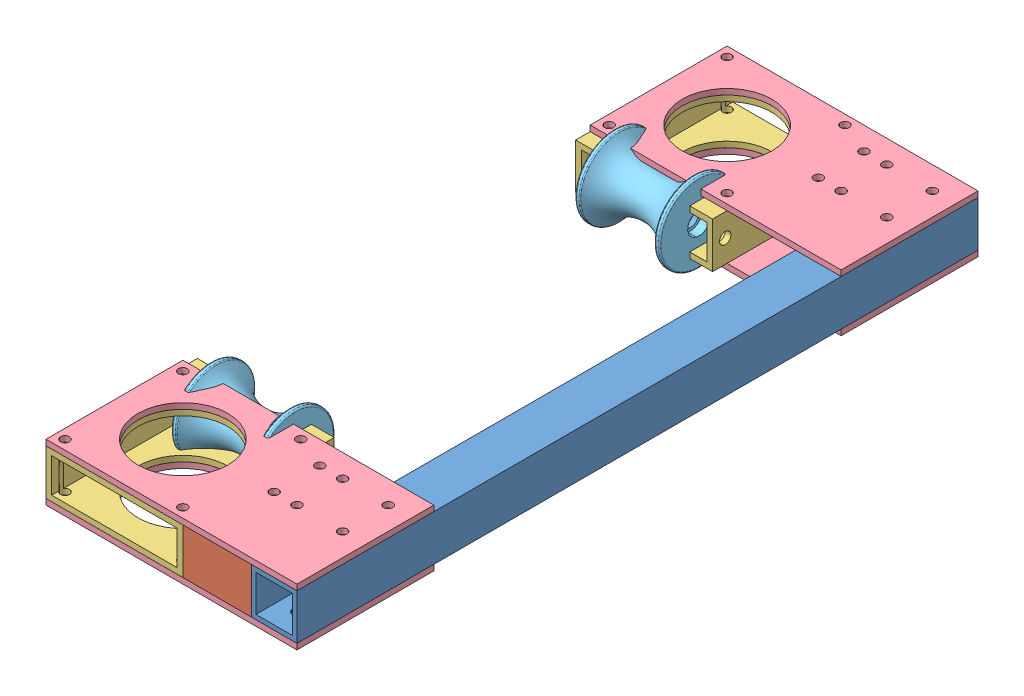
SolidWorks assembly 221-000 Asm, configuration Default. Lengths in mm.
Overall size (139.7 61.76 379.16).
11 component instances, 5 part files, 34 mates.
Components (placement in the parent):
- 221-003-1: 221-003 [Default] at origin size (25.4 25.4 379.16)
- 221-002-1: 221-002 [Default] at (-19.05 25.4 189.5818) x (0 0 -1) z (-1 0 0) size (50.8 25.4 38.1)
- 221-001-1: 221-001 [Default] at (-114.3 25.4 140.3058) x (1 0 0) z (0 1 0) size (76.2 84.26 25.4)
- 221-001-2: 221-001 [Default] at (-114.3 0 -140.3058) x (1 0 0) z (0 -1 0) size (76.2 84.26 25.4)
- 221-002-2: 221-002 [Default] at (-19.05 0 -189.5818) x (0 0 1) z (-1 0 0) size (50.8 25.4 38.1)
- 221-004-1: 221-004 [Rev 1.1] at (0 25.4 0) x (1 0 0) z (0 1 0) size (139.7 76.2 3.17)
- 221-004-2: 221-004 [Rev 1.1] at (0 25.4 302.9636) x (1 0 0) z (0 1 0) size (139.7 76.2 3.17)
- 221-004-3: 221-004 [Rev 1.1] at (0 -3.175 0) x (1 0 0) z (0 1 0) size (139.7 76.2 3.17)
- 221-004-4: 221-004 [Rev 1.1] at (0 -3.175 302.9636) x (1 0 0) z (0 1 0) size (139.7 76.2 3.17)
- 200-001 Roller 3-1: 200-001 Roller 3 [Default] at (-76.2 12.7 -112.3658) x (0 -1 0) z (0 0 1) size (43.94 46.98 43.94)
- 200-001 Roller 3-2: 200-001 Roller 3 [Default] at (-76.2 12.7 112.3658) x (0 -0.780395 0.625287) z (0 0.625287 0.780395) size (43.94 46.98 43.94)
Mates (geometry in assembly coordinates):
- Coincident1: coincident: plane of 221-002-1 through (-38.1 25.4 189.5818) normal (-1 0 0); plane of 221-001-1 through (-38.1 25.4 91.0298) normal (1 0 0)
- Coincident2: coincident: plane of 221-002-1 through (-38.1 25.4 189.5818) normal (0 1 0); plane of 221-001-1 through (-114.3 25.4 91.0298) normal (0 1 0)
- Coincident3: coincident: plane of 221-002-1 through (-38.1 25.4 189.5818) normal (0 0 1); plane of 221-001-1 through (-114.3 25.4 189.5818) normal (0 0 1)
- Coincident4: coincident: plane of 221-003-1 through (0 0 189.5818) normal (-1 0 0); plane of 221-002-1 through (0 25.4 189.5818) normal (1 0 0)
- Coincident5: coincident: plane of 221-003-1 through (0 25.4 189.5818) normal (0 1 0); plane of 221-002-1 through (-38.1 25.4 189.5818) normal (0 1 0)
- Coincident6: coincident: plane of 221-003-1 through (0 0 189.5818) normal (0 0 1); plane of 221-002-1 through (-38.1 25.4 189.5818) normal (0 0 1)
- Coincident7: coincident: plane of 221-001-2 through (-38.1 0 -91.0298) normal (1 0 0); plane of 221-002-2 through (-38.1 0 -189.5818) normal (-1 0 0)
- Coincident8: coincident: plane of 221-001-2 through (-114.3 0 -91.0298) normal (0 -1 0); plane of 221-002-2 through (-38.1 0 -189.5818) normal (0 -1 0)
- Coincident9: coincident: plane of 221-001-2 through (-114.3 0 -189.5818) normal (0 0 -1); plane of 221-002-2 through (-38.1 0 -189.5818) normal (0 0 -1)
- Coincident10: coordinate: point of 221-003-1; point of assembly
- Coincident11: coincident: plane of 221-003-1 through (0 25.4 189.5818) normal (0 1 0); plane of 221-002-2 through (-38.1 25.4 -189.5818) normal (0 1 0)
- Coincident12: coincident: plane of 221-003-1 through (0 0 189.5818) normal (-1 0 0); plane of 221-002-2 through (0 0 -189.5818) normal (1 0 0)
- Coincident13: coincident: plane of 221-003-1 through (0 0 -189.5818) normal (0 0 -1); plane of 221-002-2 through (-38.1 0 -189.5818) normal (0 0 -1)
- Concentric1: concentric: cylinder of 221-001-2 through (-38.1 12.7 -100.584) axis (-1 0 0) radius 3.175; cylinder of ? through (-81.153 12.7 -100.584) axis (-1 0 0) radius 3.81
- Width1: width: plane of ? through (-93.853 12.7 -100.584) normal (-1 0 0); plane of ? through (-58.547 12.7 -100.584) normal (1 0 0); plane of 221-001-2 through (-111.125 0 -66.548) normal (1 0 0); plane of 221-001-2 through (-41.275 0 -66.548) normal (-1 0 0)
- Concentric2: concentric: circle of 221-001-1; cylinder of ? through (-81.153 12.7 100.584) axis (-1 0 0) radius 3.81
- Width2: width: plane of ? through (-93.853 12.7 100.584) normal (-1 0 0); plane of ? through (-58.547 12.7 100.584) normal (1 0 0); plane of 221-001-1 through (-41.275 25.4 66.548) normal (-1 0 0); plane of 221-001-1 through (-111.125 25.4 66.548) normal (1 0 0)
- InPlace1: in place: plane of 221-003-1 through (0 25.4 155.575) normal (0 1 0); plane of 221-004-1 through (0 25.4 0) normal (0 1 0); moOrthogonalPlaneRef_w of 221-003-1 through (0 25.4 155.575) normal (0 1 0); plane of 221-004-1 through (0 25.4 0) normal (0 0 -1); plane of 221-003-1 through (0 25.4 155.575) normal (0 1 0); plane of 221-004-1 through (0 25.4 0) normal (1 0 0); plane of 221-003-1 through (0 25.4 189.5818) normal (0 1 0); unknown of 221-004-1
- Coincident14: coincident: plane of 221-003-1; plane of 221-004-1
- Coincident15: coincident: moOrthogonalPlaneRef_w of 221-003-1 through (0 25.4 0) normal (0 0 -1); plane of 221-004-1 through (0 25.4 0) normal (0 0 -1)
- Coincident16: coincident: moOrthogonalPlaneRef_w of 221-003-1 through (0 25.4 0) normal (-1 0 0); plane of 221-004-1 through (0 25.4 0) normal (1 0 0)
- Concentric3: concentric: cylinder of 221-001-2 through (-38.1 12.7 -112.3658) axis (-1 0 0) radius 3.175; cylinder of 200-001 Roller 3-1 through (-52.7097 12.7 -112.3658) axis (1 0 0) radius 6.35
- Concentric4: concentric: cylinder of 221-001-1 through (-38.1 12.7 112.3658) axis (-1 0 0) radius 3.175; cylinder of 200-001 Roller 3-2 through (-52.7097 12.7 112.3658) axis (1 0 0) radius 6.35
- Coincident14: coincident: plane of 200-001 Roller 3-1 through (-99.6903 12.7 -112.3658) normal (-1 0 0); plane of 200-001 Roller 3-2 through (-99.6903 12.7 112.3658) normal (-1 0 0)
- Width3: width: plane of 200-001 Roller 3-1 through (-99.6903 12.7 -112.3658) normal (-1 0 0); plane of 200-001 Roller 3-1 through (-52.7097 12.7 -112.3658) normal (1 0 0); plane of 221-001-2 through (-41.275 0 -91.0298) normal (-1 0 0); plane of 221-001-2 through (-111.125 0 -91.0298) normal (1 0 0)
- Concentric5: concentric: cylinder of 221-001-1 through (-76.2 52.578 151.4818) axis (0 -1 0) radius 24.972; cylinder of 221-004-4 through (-76.2 0 151.4818) axis (0 -1 0) radius 24.972
- Coincident15: coincident: plane of 221-001-1 through (-114.3 25.4 189.5818) normal (0 0 1); plane of 221-004-4 through (-114.3 0 189.5818) normal (0 0 1)
- Concentric6: concentric: cylinder of 221-001-1 through (-76.2 52.578 151.4818) axis (0 -1 0) radius 24.972; cylinder of 221-004-2 through (-76.2 28.575 151.4818) axis (0 -1 0) radius 24.972
- Coincident16: coincident: plane of 221-001-1 through (-114.3 25.4 189.5818) normal (0 0 1); plane of 221-004-2 through (-114.3 28.575 189.5818) normal (0 0 1)
- Concentric7: concentric: cylinder of 221-001-2 through (-76.2 -27.178 -151.4818) axis (0 1 0) radius 24.972; cylinder of 221-004-3 through (-76.2 0 -151.4818) axis (0 -1 0) radius 24.972
- Coincident17: coincident: plane of 221-001-2 through (-114.3 0 -189.5818) normal (0 0 -1); plane of 221-004-3 through (-114.3 0 -189.5818) normal (0 0 -1)
- Coincident18: coincident: plane of 221-001-1 through (-114.3 0 91.0298) normal (0 -1 0); plane of 221-004-4 through (0 0 302.9636) normal (0 1 0)
- Coincident19: coincident: plane of 221-001-2 through (-114.3 0 -91.0298) normal (0 -1 0); plane of 221-004-3 through (0 0 0) normal (0 1 0)
- Coincident20: coincident: plane of 221-001-1 through (-114.3 25.4 91.0298) normal (0 1 0); plane of 221-004-2 through (0 25.4 302.9636) normal (0 -1 0)
